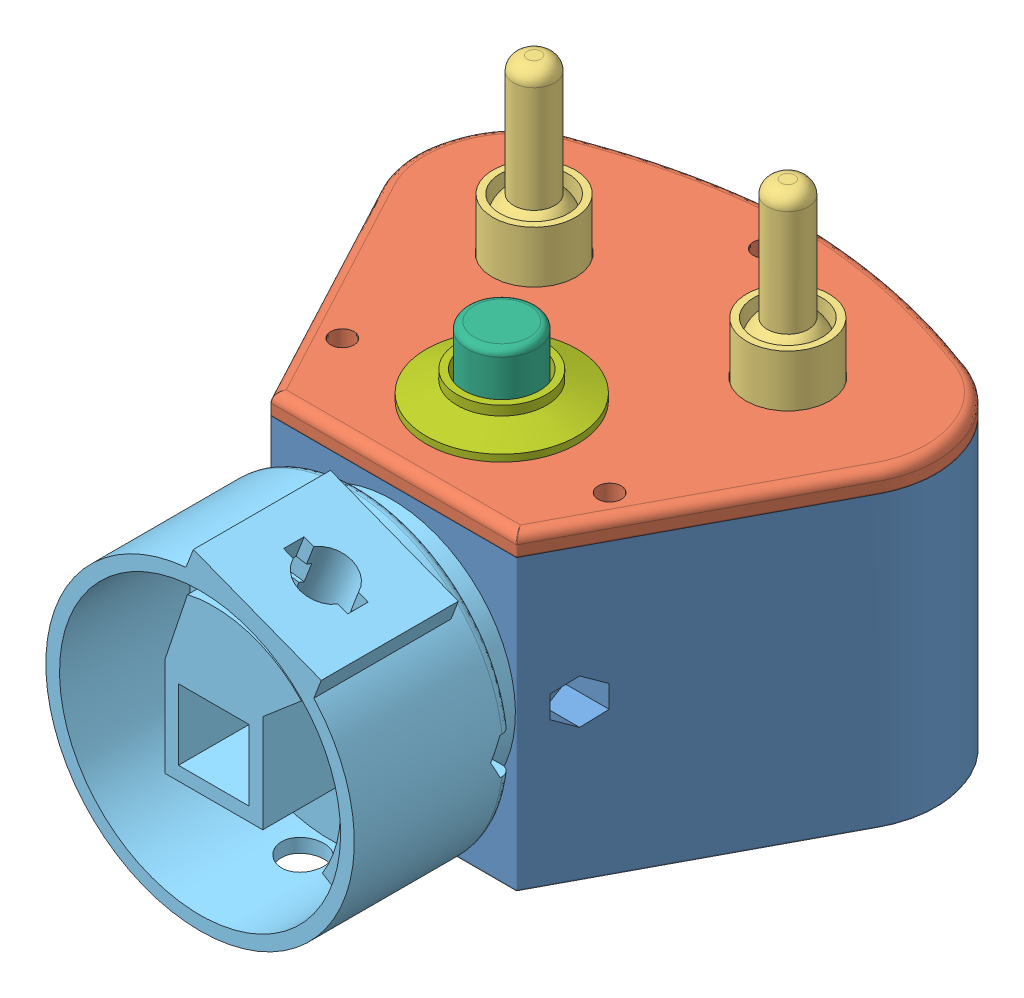
SolidWorks assembly 206_switchbox, configuration По умолчанию. Lengths in mm.
Overall size (86.24 73.1 93.52).
9 component instances, 8 part files, 21 mates.
Components (placement in the parent):
- 206h_sw_box_206h01-1: 206h_sw_box_206h01 [По умолчанию] at origin size (76.19 42.1 60.73)
- 206h_sw_box_cover_206h02-1: 206h_sw_box_cover_206h02 [По умолчанию] at (0 42.1 0) size (86.24 11.85 75.65)
- KN3(C)-123AP-1: KN3(C)-123AP [По умолчанию] at (17.8813 29 0) x (0.982908 0 0.184096) z (-0.184096 0 0.982908) size (15.8 46.3 29)
- KN3(C)-123AP-2: KN3(C)-123AP [По умолчанию] at (-16.2693 29 2.8597) size (15.8 46.3 29)
- pbs-10b2-1: pbs-10b2 [По умолчанию] at (0 29.1 23.8517) x (0.997467 0 -0.071135) z (0.071135 0 0.997467) size (9.4 20 9.4)
- single_collective_head_i2c_connector_housing_single_collective12-1: single_collective_head_i2c_connector_housing_single_collective12 [По умолчанию] at (-0.05 22.55 67.8096) x (-1 0 0) z (0 -1 0) size (45 28 47.7)
- 206h_sw_starter_btn_206h03-1: 206h_sw_starter_btn_206h03 [По умолчанию] at (0 43.1 23.8517) x (0.667085 0 -0.744982) z (0.744982 0 0.667085) size (10 12 10)
- 206h_sw_starter_btn_cover_206h04-1: 206h_sw_starter_btn_cover_206h04 [По умолчанию] at (0 42.1 23.8517) size (26 7 26)
- 206h_tj8p8c_cap_206h07-1: 206h_tj8p8c_cap_206h07 [По умолчанию] at (0 0 19.6096) x (-1 0 0) z (0 0 1) size (26 3 26)
Mates (geometry in assembly coordinates):
- Concentric1: concentric aligned: cylinder of 206h_sw_box_206h01-1 through (-19.5 0.1 27.6096) axis (0 -1 0) radius 1.7; cylinder of 206h_sw_box_cover_206h02-1 through (-19.5 42.2 27.6096) axis (0 -1 0) radius 1.7
- Concentric2: concentric aligned: cylinder of 206h_sw_box_206h01-1 through (19.5 0.1 27.6096) axis (0 -1 0) radius 1.7; cylinder of 206h_sw_box_cover_206h02-1 through (19.5 42.2 27.6096) axis (0 -1 0) radius 1.7
- Coincident1: coincident anti-aligned: plane of 206h_sw_box_206h01-1 through (-22.492 42.1 31.0272) normal (0 1 0); plane of 206h_sw_box_cover_206h02-1 through (21.6267 42.1 -1.0743) normal (0 -1 0)
- Concentric3: concentric aligned: cylinder of 206h_sw_box_cover_206h02-1 through (17.8813 42.2 0) axis (0 -1 0) radius 6.1; cylinder of KN3(C)-123AP-1 through (17.8813 52.6 0) axis (0 -1 0) radius 6
- Coincident2: coincident anti-aligned: plane of 206h_sw_box_cover_206h02-1 through (21.6267 42.1 -1.0743) normal (0 -1 0); plane of KN3(C)-123AP-1 through (17.8813 42.1 0) normal (0 1 0)
- Concentric4: concentric aligned: cylinder of 206h_sw_box_cover_206h02-1 through (-16.2693 42.2 2.8597) axis (0 -1 0) radius 6.1; cylinder of KN3(C)-123AP-2 through (-16.2693 52.6 2.8597) axis (0 -1 0) radius 6
- Coincident3: coincident anti-aligned: plane of 206h_sw_box_cover_206h02-1 through (21.6267 42.1 -1.0743) normal (0 -1 0); plane of KN3(C)-123AP-2 through (-16.2693 42.1 2.8597) normal (0 1 0)
- Parallel1: parallel anti-aligned: plane of 206h_sw_box_206h01-1 through (14.8 -35.0213 27.6096) normal (0 0 -1); plane of KN3(C)-123AP-2 through (-8.3693 42.1 17.3597) normal (0 0 1)
- Distance1: distance = 12.2 mm aligned: plane of single_collective_head_i2c_connector_housing_single_collective12-1 through (-0.05 22.55 39.8096) normal (0 0 -1); plane of 206h_sw_box_206h01-1 through (14.8 -35.0213 27.6096) normal (0 0 -1)
- Coincident8: coincident aligned: plane of 206h_sw_box_206h01-1 through (5.1 17.4 39.6808) normal (-1 0 0); plane of single_collective_head_i2c_connector_housing_single_collective12-1 through (5.1 17.4 39.8096) normal (-1 0 0)
- Coincident9: coincident aligned: plane of 206h_sw_box_206h01-1 through (-5.1 17.4 39.6808) normal (0 1 0); plane of single_collective_head_i2c_connector_housing_single_collective12-1 through (-5.2 17.4 39.8096) normal (0 1 0)
- Concentric7: concentric aligned: cylinder of 206h_sw_box_cover_206h02-1 through (0 40.1 23.8517) axis (0 1 0) radius 7; cylinder of pbs-10b2-1 through (0 37.1 23.8517) axis (0 1 0) radius 3.4
- Concentric8: concentric aligned: cylinder of 206h_sw_box_cover_206h02-1 through (0 40.1 23.8517) axis (0 1 0) radius 7; cylinder of pbs-10b2-1 through (0 37.1 23.8517) axis (0 1 0) radius 3.4
- Coincident11: coincident anti-aligned: plane of 206h_sw_box_cover_206h02-1 through (0 37.1 23.8517) normal (0 -1 0); plane of pbs-10b2-1 through (0 37.1 23.8517) normal (0 1 0)
- Concentric9: concentric anti-aligned: cylinder of pbs-10b2-1 through (0 45.8 23.8517) axis (0 1 0) radius 2.85; cylinder of 206h_sw_starter_btn_206h03-1 through (0 49.1 23.8517) axis (0 -1 0) radius 3
- Coincident12: coincident anti-aligned: plane of pbs-10b2-1 through (0 49.1 23.8517) normal (0 1 0); plane of 206h_sw_starter_btn_206h03-1 through (0 49.1 23.8517) normal (0 -1 0)
- Concentric10: concentric anti-aligned: cylinder of 206h_sw_box_cover_206h02-1 through (0 40.1 23.8517) axis (0 1 0) radius 7; cylinder of 206h_sw_starter_btn_cover_206h04-1 through (0 45.1 23.8517) axis (0 -1 0) radius 7
- Coincident13: coincident anti-aligned: plane of 206h_sw_box_cover_206h02-1 through (-28.8204 45.1 19.1493) normal (0 1 0); plane of 206h_sw_starter_btn_cover_206h04-1 through (0 45.1 23.8517) normal (0 -1 0)
- Coincident14: coincident: plane of 206h_sw_box_206h01-1 through (21.6267 0 -1.0743) normal (0 -1 0); plane of 206h_tj8p8c_cap_206h07-1 through (-54.3155 0 19.6096) normal (0 1 0)
- Coincident15: coincident: plane of 206h_sw_box_206h01-1 through (7.6 42.1 26.1096) normal (0 0 -1); plane of 206h_tj8p8c_cap_206h07-1 through (-61.9155 -3 26.1096) normal (0 0 -1)
- Coincident16: coincident aligned: plane of 206h_sw_box_206h01-1 through (-7.6 42.1 26.1096) normal (1 0 0); plane of 206h_tj8p8c_cap_206h07-1 through (-7.6 -3 26.1096) normal (1 0 0)
